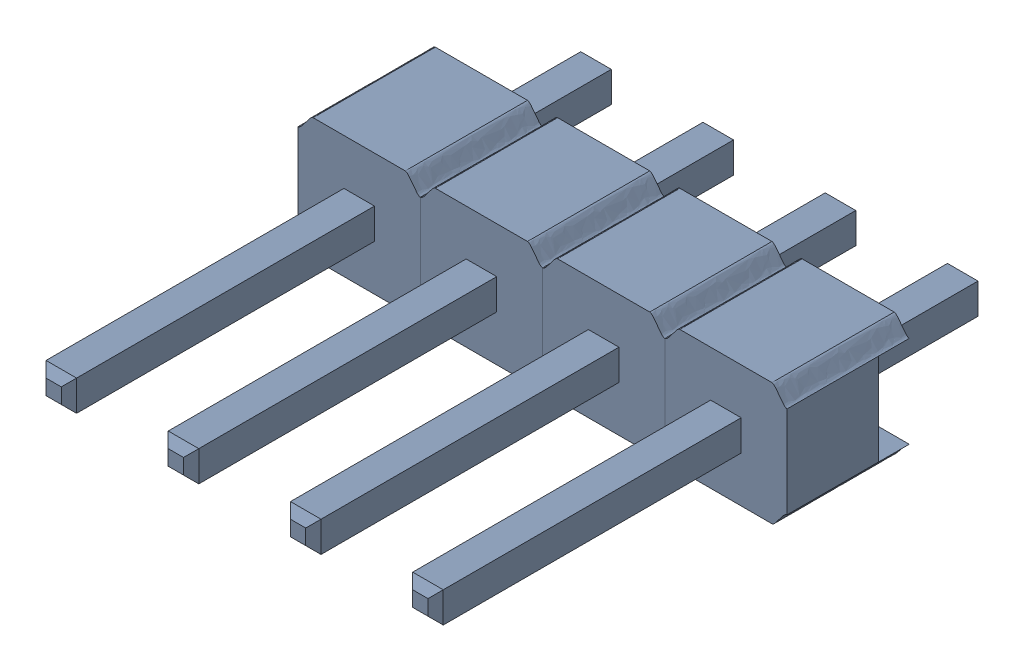
SolidWorks assembly Pin Header 1x4 TH Pitch 2.54mm v2 (1), configuration Default. Lengths in mm.
Overall size (10.16 2.58 11.43).
12 component instances, 2 part files, 0 mates.
Components (placement in the parent):
- asm_pin (1)-1: asm_pin (1) [Default] at origin size (2.54 2.58 11.43)
  - spacer (1)_1-1: spacer (1)_1 [Default] at origin size (2.54 2.58 2.54)
  - pin (1)_1-1: pin (1)_1 [Default] at origin size (0.64 0.64 11.43)
- asm_pin (1)_1-1: asm_pin (1)_1 [Default] at (2.54 0 0) size (2.54 2.58 11.43)
  - spacer (1)_1-1: spacer (1)_1 [Default] at origin size (2.54 2.58 2.54)
  - pin (1)_1-1: pin (1)_1 [Default] at origin size (0.64 0.64 11.43)
- asm_pin (1)_2-1: asm_pin (1)_2 [Default] at (5.08 0 0) size (2.54 2.58 11.43)
  - spacer (1)_1-1: spacer (1)_1 [Default] at origin size (2.54 2.58 2.54)
  - pin (1)_1-1: pin (1)_1 [Default] at origin size (0.64 0.64 11.43)
- asm_pin (1)_3-1: asm_pin (1)_3 [Default] at (7.62 0 0) size (2.54 2.58 11.43)
  - spacer (1)_1-1: spacer (1)_1 [Default] at origin size (2.54 2.58 2.54)
  - pin (1)_1-1: pin (1)_1 [Default] at origin size (0.64 0.64 11.43)
